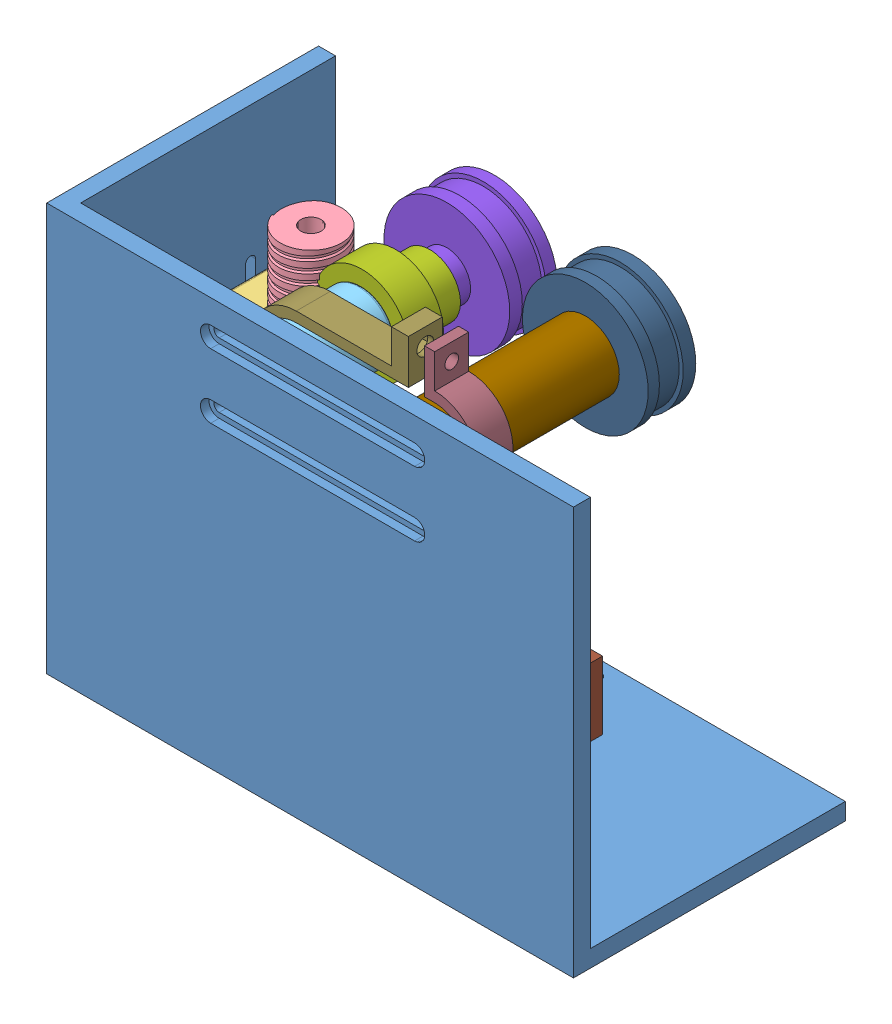
SolidWorks assembly 装配体2, configuration 默认. Lengths in mm.
Overall size (155 125.47 80).
18 component instances, 13 part files, 36 mates.
Components (placement in the parent):
- 支架-1: 支架 [默认] at origin size (155 120 80)
- 装配体-1: 装配体 [默认] at (30.5 -45.1244 40) x (-1 0 0) z (0 0 -1) size (45.5 73.2 40)
  - 电机-1: 电机 [默认] at origin size (36.5 73.2 36.5)
  - 电机支架-1: 电机支架 [默认] at (25.5 1.5 20) x (0 -1 0) z (0 0 -1) size (41 45.5 40)
- 蜗杆-1: 蜗杆 [默认] at (37.75 -38.8244 40) x (-0.943371 0 0.331739) z (0 1 0) size (18.01 18.93 32.45)
- 涡轮底座-1: 涡轮底座 [默认] at (70.25 -7 72) x (0 -1 0) z (0 0 1) size (25 25 38)
- 轴承_8_12_3.5-2: 轴承_8_12_3.5 [默认] at (57.75 -19.5 41) size (12 12 4)
- 蜗轮-2: 蜗轮 [默认] at (57.75 -19.5 45) x (0.437234 0.899348 0) z (0 0 -1) size (28 28 20)
- 轮盘(3)-1: 轮盘(3) [默认] at (57.75 -19.5 20) x (0.463561 0.886065 0) z (0 0 -1) size (37 37 31)
- 从动轮底座-1: 从动轮底座 [默认] at (85.9925 -7 72) size (25 25 67)
- 轮盘(1)-1: 轮盘(1) [默认] at (98.4925 -19.5 6) x (0.999997 0.002405 0) z (0 0 1) size (37 37 14)
- 轴承_8_12_3.5-4: 轴承_8_12_3.5 [默认] at (98.4925 -19.5 16) size (12 12 4)
- 深孔支架-1: 深孔支架 [默认] at (61.25 -115 23.6789) x (1 0 0) z (0 1 0) size (61 20 40)
- 轴承_8_12_3.5-3: 轴承_8_12_3.5 [默认] at (57.75 -19.5 37) x (0.999999 -0.00148 0) z (0 0 1) size (12 12 4)
- 轴承_8_12_3.5-5: 轴承_8_12_3.5 [默认] at (98.4925 -19.5 12) size (12 12 4)
- 轴承_8_12_3.5-6: 轴承_8_12_3.5 [默认] at (98.4925 -19.5 8) size (12 12 4)
- 紧固装置1-1: 紧固装置1 [默认] at (57.75 -19.5 54.3149) size (46 46 10)
- 紧固装置2-1: 紧固装置2 [默认] at (98.4925 -19.5 64.3149) x (-1 0 0) z (0 0 -1) size (16 46 10)
Mates (geometry in assembly coordinates):
- 重合1: coincident anti-aligned: plane of 支架-1 through (5 0 80) normal (1 0 0); plane of 装配体-1/电机支架-1 through (5 -84.6244 20) normal (-1 0 0)
- 平行1: parallel aligned: plane of 支架-1 through (0 0 80) normal (0 1 0); plane of 装配体-1/电机支架-1 through (30.5 -43.6244 40) normal (0 1 0)
- 槽口1: slot anti-aligned: cylinder of 装配体-1/电机支架-1 through (5 -52.6244 55) axis (-1 0 0) radius 1.85; plane of 支架-1 through (-0.001 -40 53.5) normal (0 0 1); cylinder of 支架-1 through (-0.001 -80 55) axis (1 0 0) radius 1.5
- 重合3: coincident anti-aligned: plane of 装配体-1/电机-1 through (36.1423 -38.8244 40) normal (0 1 0); plane of 蜗杆-1 through (37.75 -38.8244 40) normal (0 -1 0)
- 同心4: concentric anti-aligned: cylinder of 装配体-1/电机-1 through (37.75 -38.8244 40) axis (0 1 0) radius 3; cylinder of 蜗杆-1 through (37.75 -6.3742 40) axis (0 -1 0) radius 3
- 槽口2: slot anti-aligned: cylinder of 装配体-1/电机支架-1 through (5 -76.6244 55) axis (-1 0 0) radius 1.85; cylinder of 支架-1 through (-0.001 -80 55) axis (1 0 0) radius 1.5; cylinder of 支架-1 through (-0.001 -40 55) axis (1 0 0) radius 1.5
- 槽口5: slot aligned: cylinder of 涡轮底座-1 through (48.25 -29 75) axis (0 0 -1) radius 1.5; cylinder of 支架-1 through (108.25 -29 80) axis (0 0 -1) radius 1.5; cylinder of 支架-1 through (48.25 -29 80) axis (0 0 -1) radius 1.5
- 重合4: coincident anti-aligned: plane of 支架-1 through (155 0 75) normal (0 0 -1); plane of 涡轮底座-1 through (70.25 -7 75) normal (0 0 1)
- 槽口6: slot aligned: cylinder of 涡轮底座-1 through (67.25 -29 75) axis (0 0 -1) radius 1.5; cylinder of 支架-1 through (108.25 -29 80) axis (0 0 -1) radius 1.5; cylinder of 支架-1 through (48.25 -29 80) axis (0 0 -1) radius 1.5
- 重合5: coincident anti-aligned: plane of 涡轮底座-1 through (57.75 -19.5 45) normal (0 0 -1); plane of 轴承_8_12_3.5-2 through (57.75 -19.5 45) normal (0 0 1)
- 同心10: concentric aligned: cylinder of 轴承_8_12_3.5-2 through (57.75 -19.5 45) axis (0 0 -1) radius 6; cylinder of 蜗轮-2 through (57.75 -19.5 45) axis (0 0 -1) radius 6
- 同心11: concentric anti-aligned: cylinder of 涡轮底座-1 through (57.75 -19.5 37) axis (0 0 1) radius 3; cylinder of 轴承_8_12_3.5-2 through (57.75 -19.5 45) axis (0 0 -1) radius 3
- 重合7: coincident anti-aligned: plane of 涡轮底座-1 through (57.75 -19.5 45) normal (0 0 -1); plane of 蜗轮-2 through (57.75 -19.5 45) normal (0 0 1)
- 同心12: concentric aligned: cylinder of 蜗轮-2 through (57.75 -19.5 45) axis (0 0 -1) radius 6; cylinder of 轮盘(3)-1 through (57.75 -19.5 37) axis (0 0 -1) radius 5.75
- 槽口7: slot aligned: cylinder of 从动轮底座-1 through (107.9925 -29 75) axis (0 0 -1) radius 1.5; cylinder of 支架-1 through (108.25 -29 80) axis (0 0 -1) radius 1.5; cylinder of 支架-1 through (48.25 -29 80) axis (0 0 -1) radius 1.5
- 槽口8: slot aligned: cylinder of 从动轮底座-1 through (107.9925 -10 75) axis (0 0 -1) radius 1.5; cylinder of 支架-1 through (108.25 -10 80) axis (0 0 -1) radius 1.5; cylinder of 支架-1 through (48.25 -10 80) axis (0 0 -1) radius 1.5
- 重合9: coincident anti-aligned: plane of 支架-1 through (155 0 75) normal (0 0 -1); plane of 从动轮底座-1 through (85.9925 -7 75) normal (0 0 1)
- 重合10: coincident anti-aligned: plane of 从动轮底座-1 through (98.4925 -19.5 20) normal (0 0 -1); plane of 轴承_8_12_3.5-4 through (98.4925 -19.5 20) normal (0 0 1)
- 重合11: coincident anti-aligned: plane of 从动轮底座-1 through (98.4925 -19.5 20) normal (0 0 -1); plane of 轮盘(1)-1 through (98.4925 -19.5 20) normal (0 0 1)
- 槽口9: slot anti-aligned: cylinder of 深孔支架-1 through (66.25 -95 27.6789) axis (0 -1 0) radius 1.5; plane of 支架-1 through (67.75 -120 5) normal (-1 0 0); cylinder of 支架-1 through (66.25 -120 5) axis (0 1 0) radius 1.5
- 槽口10: slot anti-aligned: cylinder of 深孔支架-1 through (86.25 -95 39.6789) axis (0 -1 0) radius 1.5; cylinder of 支架-1 through (86.25 -120 65) axis (0 1 0) radius 1.8599; cylinder of 支架-1 through (86.25 -120 5) axis (0 1 0) radius 1.8599
- 重合12: coincident anti-aligned: plane of 支架-1 through (155 -115 80) normal (0 1 0); plane of 深孔支架-1 through (61.25 -115 23.6789) normal (0 -1 0)
- 重合13: coincident anti-aligned: plane of 轴承_8_12_3.5-2 through (57.75 -19.5 41) normal (0 0 -1); plane of 轴承_8_12_3.5-3 through (57.75 -19.5 41) normal (0 0 1)
- 同心16: concentric anti-aligned: cylinder of 涡轮底座-1 through (57.75 -19.5 37) axis (0 0 1) radius 3; cylinder of 轴承_8_12_3.5-3 through (57.75 -19.5 41) axis (0 0 -1) radius 3
- 重合14: coincident anti-aligned: plane of 涡轮底座-1 through (57.75 -19.5 37) normal (0 0 -1); plane of 轮盘(3)-1 through (57.75 -19.5 37) normal (0 0 1)
- 同心17: concentric anti-aligned: cylinder of 从动轮底座-1 through (98.4925 -19.5 8) axis (0 0 1) radius 3; cylinder of 轴承_8_12_3.5-4 through (98.4925 -19.5 20) axis (0 0 -1) radius 3
- 重合15: coincident anti-aligned: plane of 轴承_8_12_3.5-4 through (98.4925 -19.5 16) normal (0 0 -1); plane of 轴承_8_12_3.5-5 through (98.4925 -19.5 16) normal (0 0 1)
- 同心18: concentric anti-aligned: cylinder of 从动轮底座-1 through (98.4925 -19.5 8) axis (0 0 1) radius 3; cylinder of 轴承_8_12_3.5-5 through (98.4925 -19.5 16) axis (0 0 -1) radius 3
- 重合16: coincident anti-aligned: plane of 轴承_8_12_3.5-5 through (98.4925 -19.5 12) normal (0 0 -1); plane of 轴承_8_12_3.5-6 through (98.4925 -19.5 12) normal (0 0 1)
- 同心19: concentric anti-aligned: cylinder of 从动轮底座-1 through (98.4925 -19.5 8) axis (0 0 1) radius 3; cylinder of 轴承_8_12_3.5-6 through (98.4925 -19.5 12) axis (0 0 -1) radius 3
- 同心20: concentric aligned: cylinder of 轮盘(1)-1 through (98.4925 -19.5 20) axis (0 0 -1) radius 6; cylinder of 轴承_8_12_3.5-4 through (98.4925 -19.5 20) axis (0 0 -1) radius 6
- 同心21: concentric anti-aligned: cylinder of 涡轮底座-1 through (57.75 -19.5 45) axis (0 0 1) radius 10; cylinder of 紧固装置1-1 through (57.75 -19.5 64.3149) axis (0 0 -1) radius 10
- 平行2: parallel aligned: plane of 支架-1 through (5 0 80) normal (1 0 0); plane of 紧固装置1-1 through (90.75 3.5 64.3149) normal (1 0 0)
- 平行4: parallel anti-aligned: plane of 支架-1 through (5 0 80) normal (1 0 0); plane of 紧固装置2-1 through (95.4925 3.5 54.3149) normal (-1 0 0)
- 同心24: concentric aligned: cylinder of 从动轮底座-1 through (98.4925 -19.5 20) axis (0 0 1) radius 10; cylinder of 紧固装置2-1 through (98.4925 -19.5 54.3149) axis (0 0 1) radius 10
- 重合22: coincident aligned: plane of 紧固装置1-1 through (57.75 -19.5 54.3149) normal (0 0 -1); plane of 紧固装置2-1 through (98.4925 -19.5 54.3149) normal (0 0 -1)
